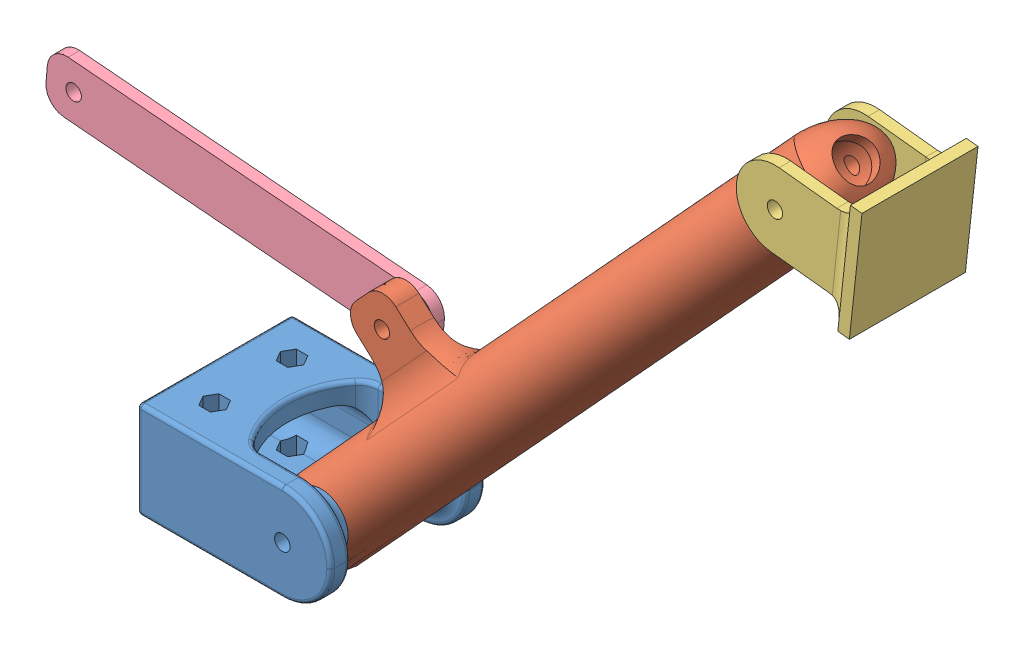
SolidWorks assembly bee-bots-arm, configuration Default. Lengths in mm.
Overall size (229.38 177.34 40).
4 component instances, 4 part files, 6 mates.
Components (placement in the parent):
- base-1: base [Default] at (-9.8206 22.3175 42.7827) size (50 25 40)
- arm-1: arm [Default] at (154.7722 160.8505 42.7808) x (-0.676026 -0.736878 0) z (0.736878 -0.676026 0) size (203.81 22.41 40.18)
- magnet-holder-1: magnet-holder [Default] at (170.8767 150.9909 42.7808) x (-0.994119 0.108297 0) z (0 0 1) size (33 30.67 30.67)
- tramsmission-rod-1: tramsmission-rod [Default] at (42.8036 58.3009 39.7808) x (0 0 -1) z (0.996423 -0.084507 0) size (3 14 100)
Mates (geometry in assembly coordinates):
- Concentric2: concentric aligned: cylinder of arm-1 through (148.012 153.4817 32.7808) axis (0 0 1) radius 2; cylinder of magnet-holder-1 through (148.012 153.4817 25.7808) axis (0 0 1) radius 2
- Tangent3: tangent anti-aligned: cylinder of arm-1 through (154.7722 160.8505 42.7808) axis (-0.676026 -0.736878 0) radius 10; plane of magnet-holder-1 through (104.3596 168.2963 52.7808) normal (0 0 -1)
- Concentric3: concentric anti-aligned: cylinder of arm-1 through (36.4202 65.8674 45.7808) axis (0 0 -1) radius 2; cylinder of tramsmission-rod-1 through (36.4202 65.8674 36.7808) axis (0 0 1) radius 2
- Coincident1: coincident anti-aligned: plane of arm-1 through (48.2982 44.7922 39.7808) normal (0 0 -1); plane of tramsmission-rod-1 through (42.8036 58.3009 39.7808) normal (0 0 1)
- Concentric4: concentric anti-aligned: cylinder of base-1 through (27.6794 22.3175 57.7827) axis (0 0 -1) radius 12.5; cylinder of arm-1 through (27.6794 22.3175 32.7808) axis (0 0 1) radius 2
- Tangent7: tangent: face of base-1; cylinder of arm-1 through (154.7722 160.8505 42.7808) axis (-0.676026 -0.736878 0) radius 10
